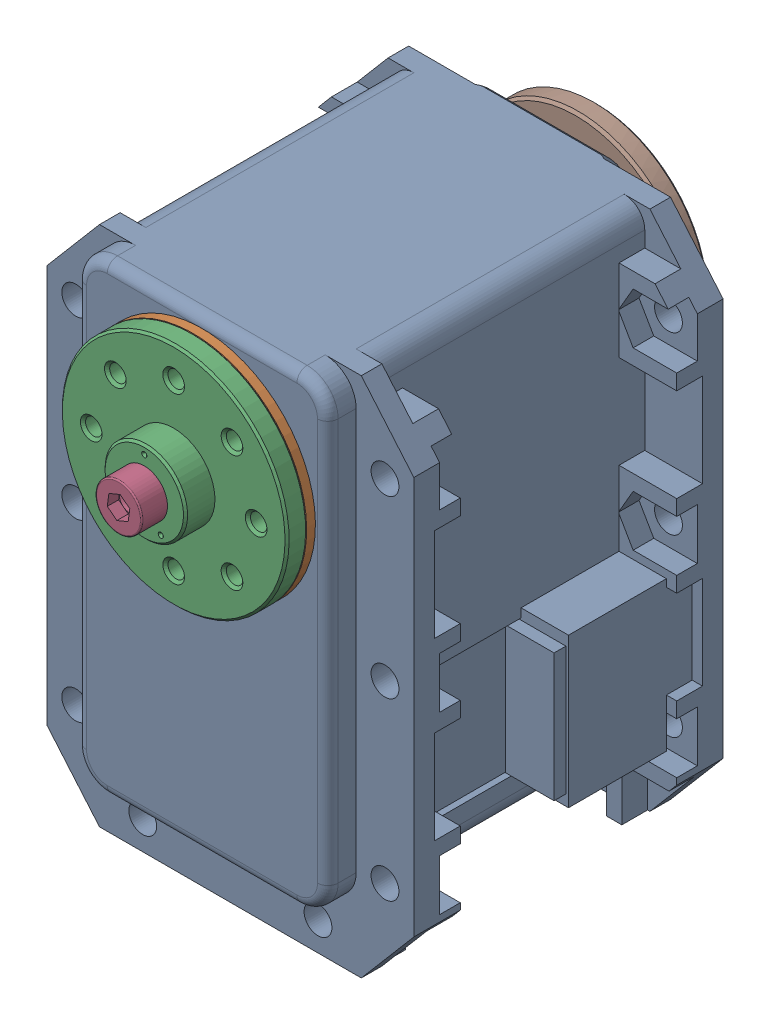
SolidWorks assembly MX-28(U)-9, configuration Default. Lengths in mm.
Overall size (35.6 54.13 48.5).
8 component instances, 7 part files, 0 mates.
Components (placement in the parent):
- dynamixel_x28series(U)-1: dynamixel_x28series(U) [Default] at origin size (35.6 50.71 41.85)
- trust_washer(U)-1: trust_washer(U) [Default] at (0 0 18.6) x (-0.666375 -0.745617 0) z (0.745617 -0.666375 0) size (22 0.85 22)
- HN07-N101(U)-1: HN07-N101(U) [Default] at (0 0 18.5) x (1 0 0) z (0 -1 0) size (22 5.85 22)
- WB_M2.5x8-1: WB_M2.5x8 [Default] at (0 0 25.85) x (0 0 -1) z (-0.991137 0.132843 0) size (10.5 4.5 4.5)
- WB_M2.5x8-2: WB_M2.5x8 [Default] at (0 0 -22.65) x (0 0 1) z (-0.936501 0.350665 0) size (10.5 4.5 4.5)
- RX28-CAP-1: RX28-CAP [Default] at (0 0 -20.35) x (-0.995735 -0.092256 0) z (0 0 -1) size (7.2 7.2 1.8)
- MF106ZZ-1: MF106ZZ [Default] at (0 0 -20.35) x (0.888333 -0.4592 0) z (-0.4592 -0.888333 0) size (11.2 3 11.2)
- HN07-i101-1: HN07-i101 [Default] at (0 0 -20.5) x (1 0 0) z (0 1 0) size (22 3.05 22)
